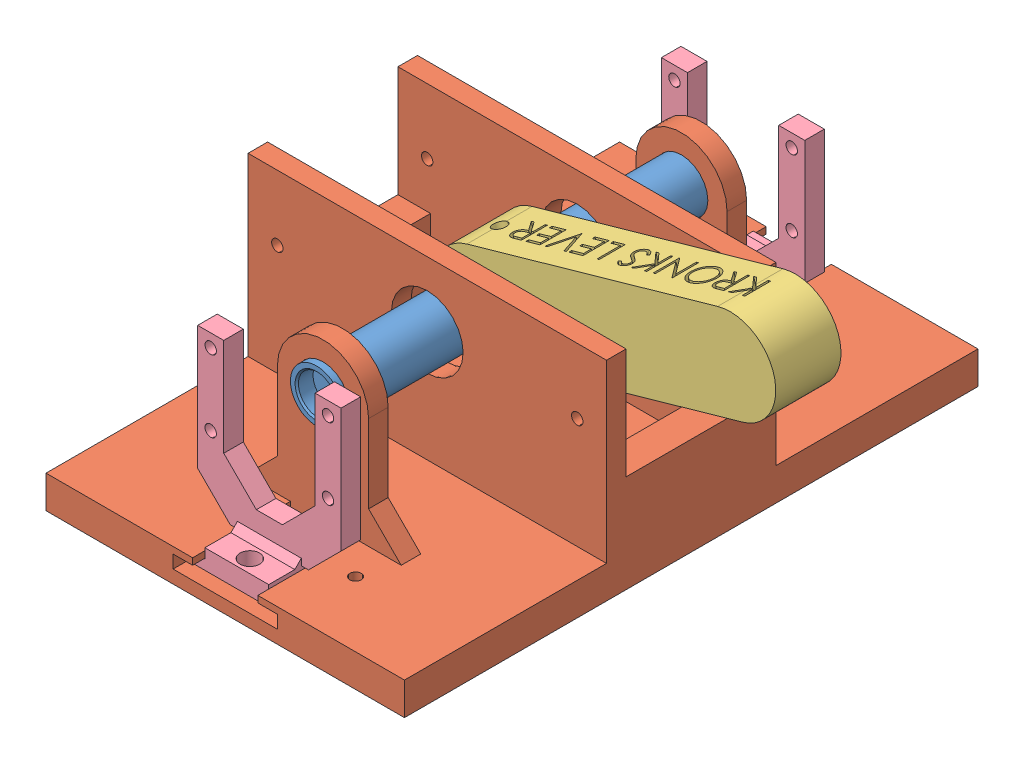
SolidWorks assembly EncoderTester9000, configuration Default. Lengths in mm.
Overall size (74.62 41.6 88).
5 component instances, 4 part files, 9 mates.
Components (placement in the parent):
- magnet_mount-1: magnet_mount [Default] at (32.1642 46.6029 30.5119) x (-0.961814 -0.273704 0) z (0 0 1) size (8 8 60)
- jig-1: jig [Default] at (32.1642 46.6029 70.5119) x (1 0 0) z (0 -1 0) size (55 88 32)
- handle-1: handle [Default] at (32.1642 46.6029 65.5119) x (-0.961814 -0.273704 0) z (0.273704 -0.961814 0) size (54 10 14)
- bracket-1: bracket [Default] at (32.1642 27.1029 23.5898) size (22 27 8)
- bracket-2: bracket [Default] at (32.1642 27.1029 97.7392) x (-1 0 0) z (0 0 -1) size (22 27 8)
Mates (geometry in assembly coordinates):
- Concentric1: concentric aligned: cylinder of magnet_mount-1 through (32.1642 46.6029 90.5119) axis (0 0 -1) radius 4; cylinder of jig-1 through (32.1642 46.6029 89.5119) axis (0 0 -1) radius 4.05
- Parallel1: parallel anti-aligned: plane of jig-1 through (32.1642 24.6029 73.5119) normal (0 -1 0)
- Width1: width aligned: plane of jig-1 through (32.1642 46.6029 31.5119) normal (0 0 -1); plane of magnet_mount-1 through (32.1642 46.6029 89.5119) normal (0 0 1); plane of jig-1 through (32.1642 46.6029 30.5119) normal (0 0 -1); plane of magnet_mount-1 through (32.1642 46.6029 90.5119) normal (0 0 1)
- Concentric2: concentric anti-aligned: cylinder of magnet_mount-1 through (32.1642 46.6029 90.5119) axis (0 0 -1) radius 4; cylinder of handle-1 through (32.1642 46.6029 55.5119) axis (0 0 1) radius 4.025
- Concentric3: concentric anti-aligned: cylinder of magnet_mount-1 through (31.0694 50.4501 60.5119) axis (0.273704 -0.961814 0) radius 0.875; cylinder of handle-1 through (34.0801 39.8702 60.5119) axis (-0.273704 0.961814 0) radius 1.05
- Coincident2: coincident anti-aligned: plane of jig-1 through (32.1642 28.6029 16.5119) normal (0 -1 0); plane of bracket-1 through (32.1642 28.6029 26.5898) normal (0 1 0)
- Width2: width anti-aligned: plane of bracket-1 through (37.0642 27.1029 26.5898) normal (1 0 0); plane of jig-1 through (27.2642 27.1029 26.5898) normal (-1 0 0); plane of bracket-1 through (37.1642 46.6029 16.5119) normal (-1 0 0); plane of jig-1 through (27.1642 46.6029 16.5119) normal (1 0 0)
- Coincident3: coincident anti-aligned: plane of jig-1 through (32.1642 28.6029 104.5119) normal (0 -1 0); plane of bracket-2 through (32.1642 28.6029 94.7392) normal (0 1 0)
- Width3: width aligned: plane of bracket-2 through (27.2642 27.1029 94.7392) normal (-1 0 0); plane of jig-1 through (37.0642 27.1029 94.7392) normal (1 0 0); plane of bracket-2 through (37.1642 46.6029 104.5119) normal (-1 0 0); plane of jig-1 through (27.1642 46.6029 104.5119) normal (1 0 0)
